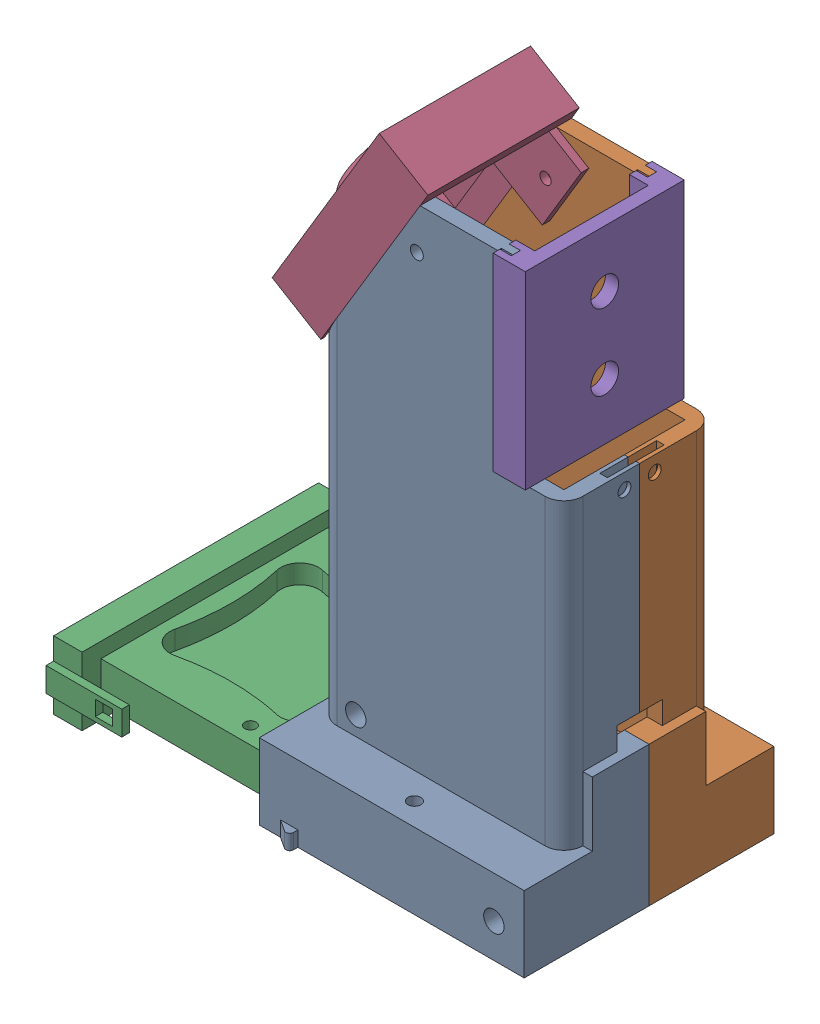
SolidWorks assembly Assem1, configuration Default. Lengths in mm.
Overall size (122.5 163.21 74).
5 component instances, 5 part files, 11 mates.
Components (placement in the parent):
- ControllerLeftSide-1: ControllerLeftSide [Default] at (28.8325 29.0765 109.4645) size (70 151.54 35.15)
- ControllerRightSide-1: ControllerRightSide [Default] at (28.8325 29.0765 109.4645) size (70 151.54 35.15)
- IMUFixture-1: IMUFixture [Default] at (-28.6675 13.0765 109.3127) x (0 0 1) z (-1 0 0) size (74 18 52.5)
- JoystickFixture-1: JoystickFixture [Default] at (-1.6205 146.6428 109.4645) x (0 0 -1) z (-0.514496 -0.857493 0) size (40 29 55)
- ButtonFixture-1: ButtonFixture [Default] at (52.3325 134.0765 109.6645) x (0 0 1) z (0 -1 0) size (42 8.5 50)
Mates (geometry in assembly coordinates):
- Coincident1: coincident aligned: line of ControllerLeftSide-1 through (-6.1675 29.0765 109.4645) axis (0 0 1); line of ControllerRightSide-1 through (-6.1675 29.0765 76.4645) axis (0 0 1)
- Coincident3: coincident anti-aligned: plane of ControllerLeftSide-1 through (-6.1675 9.0765 109.4645) normal (0 0 -1); plane of ControllerRightSide-1 through (-6.1675 9.0765 109.4645) normal (0 0 1)
- Coincident4: coincident anti-aligned: circle of ControllerLeftSide-1; circle of ControllerRightSide-1
- Coincident5: coincident anti-aligned: plane of ControllerLeftSide-1 through (20.76 160.6199 126.4645) normal (0 0 -1); plane of JoystickFixture-1 through (-5.4792 116.8878 126.4645) normal (0 0 1)
- Concentric1: concentric anti-aligned: cylinder of ControllerLeftSide-1 through (22.475 147.929 119.4645) axis (0 0 1) radius 1.7; cylinder of JoystickFixture-1 through (22.475 147.929 129.4645) axis (0 0 -1) radius 1.5
- Coincident6: coincident anti-aligned: plane of ControllerRightSide-1 through (23.3325 159.0765 89.4645) normal (-0.857493 0.514496 0); plane of JoystickFixture-1 through (11.2419 138.9254 109.4645) normal (0.857493 -0.514496 0)
- Coincident7: coincident anti-aligned: plane of ControllerRightSide-1 through (61.3325 109.0765 89.4645) normal (0 1 0); plane of ButtonFixture-1 through (48.8325 109.0765 89.6645) normal (0 -1 0)
- Coincident8: coincident anti-aligned: plane of ControllerRightSide-1 through (43.8325 159.0765 89.4645) normal (1 0 0); plane of ButtonFixture-1 through (43.8325 134.0765 109.6645) normal (-1 0 0)
- Coincident9: coincident anti-aligned: plane of ControllerLeftSide-1 through (46.8325 159.0765 126.4645) normal (0 0 -1); plane of ButtonFixture-1 through (46.8325 109.0765 126.4645) normal (0 0 1)
- Coincident10: coincident anti-aligned: plane of ControllerRightSide-1 through (-6.1675 9.0765 142.4645) normal (-1 0 0); plane of IMUFixture-1 through (-6.1675 23.0765 79.3127) normal (1 0 0)
- Coincident11: coincident aligned: plane of ControllerRightSide-1 through (28.8325 9.0765 109.4645) normal (0 -1 0); plane of IMUFixture-1 through (-58.6675 9.0765 74.3127) normal (0 -1 0)
